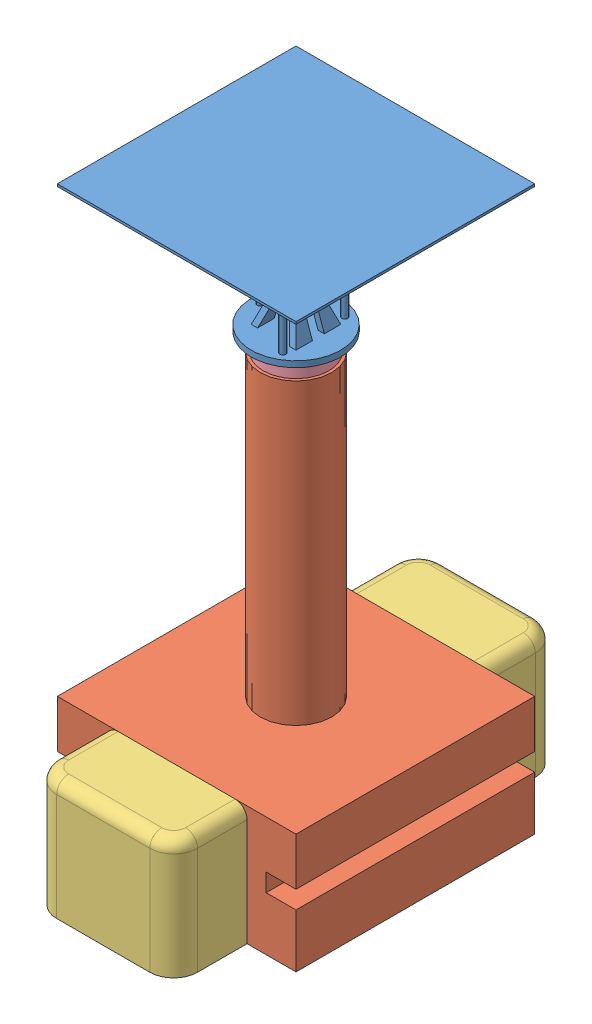
SolidWorks assembly Asseadasfasfm1, configuration Default. Lengths in mm.
Overall size (400 943.92 646).
12 component instances, 6 part files, 1 mates.
Components (placement in the parent):
- cap - Copy222-1: cap - Copy222 [Default] at (316.0811 449.0073 791.5469) size (400 264 400)
- pole-1: pole [Default] at (-434.6067 -915.3868 -1283.2894) size (400 728.1 646)
  - pilon-1: pilon [Default] at (750.6878 634.4701 2074.8363) size (400 700 400)
  - fix-1: fix [Default] at (704.1878 324.4701 2336.3363) size (236 530 123)
    - screw - Copy-1: screw - Copy [Default] at origin size (83 330 83) (hidden)
    - Part3^fix-1: Part3^fix [Default] at origin size (236 200 123) (virtual)
    - screw2 - Copy - Copy-1: screw2 - Copy - Copy [Default] at (97.0846 0 0) size (83 330 83) (hidden)
  - fix-2: fix [Default] at (797.1878 324.4701 1813.3363) x (-1 0 0) z (0 0 -1) size (236 530 123)
    - screw - Copy-1: screw - Copy [Default] at origin size (83 330 83) (hidden)
    - Part3^fix-1: Part3^fix [Default] at origin size (236 200 123) (virtual)
    - screw2 - Copy - Copy-1: screw2 - Copy - Copy [Default] at (97.0846 0 0) size (83 330 83) (hidden)
  - pilon2-1: pilon2 [Default] at (750.6878 862.5735 2074.8363) x (0.350749 0 0.936469) z (-0.936469 0 0.350749) size (110 500 110)
Mates (geometry in assembly coordinates):
- Concentric1: concentric: cylinder of cap - Copy222-1 through (316.0811 399.0073 791.5469) axis (0 1 0) radius 45; cylinder of pole-1/pilon2-1 through (316.0811 447.1867 791.5469) axis (0 -1 0) radius 50
